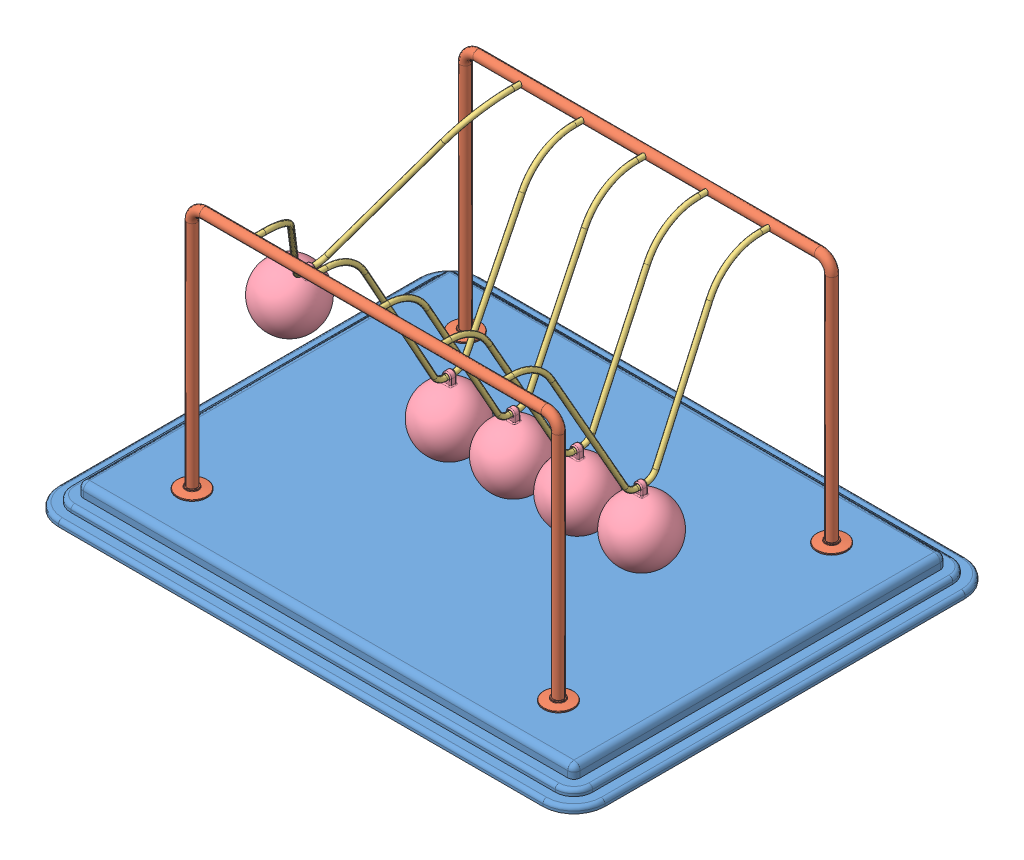
SolidWorks assembly Newtons Cradle NewtonsCradle 0256, configuration Default. Lengths in mm.
Overall size (440 222 340).
13 component instances, 4 part files, 34 mates.
Components (placement in the parent):
- Base 207,455429497569-1: Base 207,455429497569 [Default] at (-16.2968 -4.1587 11.425) size (440 20 340)
- frame NewtonsCradle 0256-1: frame NewtonsCradle 0256 [Default] at (-16.2968 144.4547 -98.575) size (319 202 24)
- frame NewtonsCradle 0256-2: frame NewtonsCradle 0256 [Default] at (-16.2968 144.4547 121.425) x (-1 0 0) z (0 0 -1) size (319 202 24)
- Hanging thing NewtonsCradle 0256-1: Hanging thing NewtonsCradle 0256 [Default] at (-157.6326 134.1825 11.425) x (0 0 1) z (-0.859985 0.510319 0) size (220 129 4)
- Hanging thing NewtonsCradle 0256-2: Hanging thing NewtonsCradle 0256 [Default] at (-66.576 122.8418 11.425) x (0 0 1) z (-0.999994 0.003446 0) size (220 129 4)
- Hanging thing NewtonsCradle 0256-3: Hanging thing NewtonsCradle 0256 [Default] at (-15.6923 122.8436 11.425) x (0 0 1) z (-0.999972 -0.007464 0) size (220 129 4)
- Hanging thing NewtonsCradle 0256-4: Hanging thing NewtonsCradle 0256 [Default] at (35.2213 122.8555 11.425) x (0 0 1) z (-0.999824 -0.018742 0) size (220 129 4)
- Hanging thing NewtonsCradle 0256-5: Hanging thing NewtonsCradle 0256 [Default] at (86.0287 122.8747 11.425) x (0 0 1) z (-0.999588 -0.028711 0) size (220 129 4)
- Sphere NewtonsCradle 0256-1: Sphere NewtonsCradle 0256 [Default] at (-195.3962 70.5436 11.425) x (0.859985 -0.510319 0) z (0 0 1) size (50 58.5 50)
- Sphere NewtonsCradle 0256-2: Sphere NewtonsCradle 0256 [Default] at (88.1533 48.9052 11.425) x (0.999588 0.028711 0) z (0 0 1) size (50 58.5 50)
- Sphere NewtonsCradle 0256-3: Sphere NewtonsCradle 0256 [Default] at (-15.14 48.8456 11.425) x (0.999972 0.007464 0) z (0 0 1) size (50 58.5 50)
- Sphere NewtonsCradle 0256-4: Sphere NewtonsCradle 0256 [Default] at (36.6081 48.8685 11.425) x (0.999824 0.018742 0) z (0 0 1) size (50 58.5 50)
- Sphere NewtonsCradle 0256-5: Sphere NewtonsCradle 0256 [Default] at (-66.831 48.8422 11.425) x (0.999994 -0.003446 0) z (0 0 1) size (50 58.5 50)
Mates (geometry in assembly coordinates):
- Coincident1: coincident anti-aligned: plane of Base-1 through (-211.2968 5.8413 156.425) normal (0 1 0); plane of frame-2 through (-175.7968 5.8413 121.425) normal (0 -1 0)
- Coincident2: coincident anti-aligned: plane of Base-1 through (-211.2968 5.8413 156.425) normal (0 1 0); plane of frame-1 through (143.2032 5.8413 -98.575) normal (0 -1 0)
- Concentric1: concentric anti-aligned: cylinder of frame-1 through (-116.2968 203.8413 -94.575) axis (0 0 -1) radius 2; cylinder of frame-2 through (-116.2968 203.8413 117.425) axis (0 0 1) radius 2
- Concentric2: concentric anti-aligned: cylinder of frame-1 through (83.7032 203.8413 -94.575) axis (0 0 -1) radius 2; cylinder of frame-2 through (83.7032 203.8413 117.425) axis (0 0 1) radius 2
- Distance1: distance = 60 mm: plane of frame-1 through (-16.2968 144.4547 -98.575) normal (0 0 1); line of Base-1 through (-211.2968 -12.1587 -158.575) axis (1 0 0)
- Distance2: distance = 60 mm: line of Base-1 through (178.7032 -12.1587 181.425) axis (-1 0 0); plane of frame-2 through (-16.2968 144.4547 121.425) normal (0 0 -1)
- Distance3: distance = 220 mm: plane of frame-2 through (-16.2968 144.4547 121.425) normal (-1 0 0); line of Base-1 through (-236.2968 -12.1587 156.425) axis (0 0 -1)
- Concentric3: concentric anti-aligned: cylinder of frame-1 through (-116.2968 203.8413 -94.575) axis (0 0 -1) radius 2; cylinder of Hanging thing-1 through (-116.2968 203.8413 111.425) axis (0 0 1) radius 2
- Concentric4: concentric anti-aligned: cylinder of frame-1 through (-116.2968 203.8413 -94.575) axis (0 0 -1) radius 2; cylinder of Hanging thing-1 through (-116.2968 203.8413 -98.575) axis (0 0 1) radius 2
- Concentric5: concentric aligned: cylinder of frame-2 through (-66.2968 203.8413 117.425) axis (0 0 1) radius 2; cylinder of Hanging thing-2 through (-66.2968 203.8413 111.425) axis (0 0 1) radius 2
- Concentric6: concentric aligned: cylinder of frame-2 through (-16.2968 203.8413 117.425) axis (0 0 1) radius 2; cylinder of Hanging thing-3 through (-16.2968 203.8413 111.425) axis (0 0 1) radius 2
- Concentric7: concentric aligned: cylinder of frame-2 through (33.7032 203.8413 117.425) axis (0 0 1) radius 2; cylinder of Hanging thing-4 through (33.7032 203.8413 111.425) axis (0 0 1) radius 2
- Concentric8: concentric aligned: cylinder of frame-2 through (83.7032 203.8413 117.425) axis (0 0 1) radius 2; cylinder of Hanging thing-5 through (83.7032 203.8413 111.425) axis (0 0 1) radius 2
- Coincident5: coincident anti-aligned: plane of frame-2 through (83.7032 203.8413 121.425) normal (0 0 -1); plane of Hanging thing-5 through (83.7032 203.8413 121.425) normal (0 0 1)
- Coincident6: coincident anti-aligned: plane of frame-2 through (33.7032 203.8413 121.425) normal (0 0 -1); plane of Hanging thing-4 through (33.7032 203.8413 121.425) normal (0 0 1)
- Coincident7: coincident anti-aligned: plane of frame-2 through (-16.2968 203.8413 121.425) normal (0 0 -1); plane of Hanging thing-3 through (-16.2968 203.8413 121.425) normal (0 0 1)
- Coincident8: coincident anti-aligned: plane of frame-2 through (-66.2968 203.8413 121.425) normal (0 0 -1); plane of Hanging thing-2 through (-66.2968 203.8413 121.425) normal (0 0 1)
- Coincident9: coincident anti-aligned: plane of frame-2 through (-116.2968 203.8413 121.425) normal (0 0 -1); plane of Hanging thing-1 through (-116.2968 203.8413 121.425) normal (0 0 1)
- Concentric9: concentric anti-aligned: cylinder of Hanging thing-1 through (-117.0163 78.8434 7.925) axis (0 0 1) radius 2; cylinder of Sphere-1 through (-117.0163 78.8434 13.925) axis (0 0 -1) radius 2
- Concentric13: concentric anti-aligned: cylinder of Hanging thing-2 through (-66.7276 78.842 7.925) axis (0 0 1) radius 2; cylinder of Sphere-5 through (-66.7276 78.842 13.925) axis (0 0 -1) radius 2
- Concentric15: concentric anti-aligned: cylinder of Hanging thing-3 through (-15.3639 78.8448 7.925) axis (0 0 1) radius 2; cylinder of Sphere-3 through (-15.3639 78.8448 13.925) axis (0 0 -1) radius 2
- Concentric16: concentric anti-aligned: cylinder of Hanging thing-5 through (87.292 78.8928 7.925) axis (0 0 1) radius 2; cylinder of Sphere-2 through (87.292 78.8928 13.925) axis (0 0 -1) radius 2
- Concentric17: concentric anti-aligned: cylinder of Hanging thing-4 through (36.0459 78.8632 7.925) axis (0 0 1) radius 2; cylinder of Sphere-4 through (36.0459 78.8632 13.925) axis (0 0 -1) radius 2
- Parallel1: parallel anti-aligned: plane of Hanging thing-1; plane of Sphere-1
- Coincident22: coincident anti-aligned: plane of Hanging thing-1; plane of Sphere-1
- Coincident12: coincident aligned: plane of Hanging thing-2 through (-66.576 122.8418 11.425) normal (0 0 1); plane of Sphere-5 through (-66.831 48.8422 11.425) normal (0 0 1)
- Coincident10: coincident aligned: plane of Hanging thing-1 through (-116.763 122.8426 11.425) normal (0 0 1); plane of Sphere-1 through (-118.5806 48.8842 11.425) normal (0 0 1)
- Coincident13: coincident anti-aligned: plane of Hanging thing-2 through (-66.576 122.8418 11.425) normal (-0.999994 0.003446 0); plane of Sphere-5 through (-66.831 48.8422 11.425) normal (0.999994 -0.003446 0)
- Coincident14: coincident anti-aligned: plane of Hanging thing-3 through (-15.6923 122.8436 11.425) normal (-0.999972 -0.007464 0); plane of Sphere-3 through (-15.14 48.8456 11.425) normal (0.999972 0.007464 0)
- Coincident15: coincident aligned: plane of Hanging thing-3 through (-15.6923 122.8436 11.425) normal (0 0 1); plane of Sphere-3 through (-15.14 48.8456 11.425) normal (0 0 1)
- Coincident18: coincident aligned: plane of Hanging thing-4 through (35.2213 122.8555 11.425) normal (0 0 1); plane of Sphere-4 through (36.6081 48.8685 11.425) normal (0 0 1)
- Coincident19: coincident anti-aligned: plane of Hanging thing-4 through (35.2213 122.8555 11.425) normal (-0.999824 -0.018742 0); plane of Sphere-4 through (36.6081 48.8685 11.425) normal (0.999824 0.018742 0)
- Coincident20: coincident anti-aligned: plane of Hanging thing-5 through (86.0287 122.8747 11.425) normal (-0.999588 -0.028711 0); plane of Sphere-2 through (88.1533 48.9052 11.425) normal (0.999588 0.028711 0)
- Coincident21: coincident aligned: plane of Hanging thing-5 through (86.0287 122.8747 11.425) normal (0 0 1); plane of Sphere-2 through (88.1533 48.9052 11.425) normal (0 0 1)
